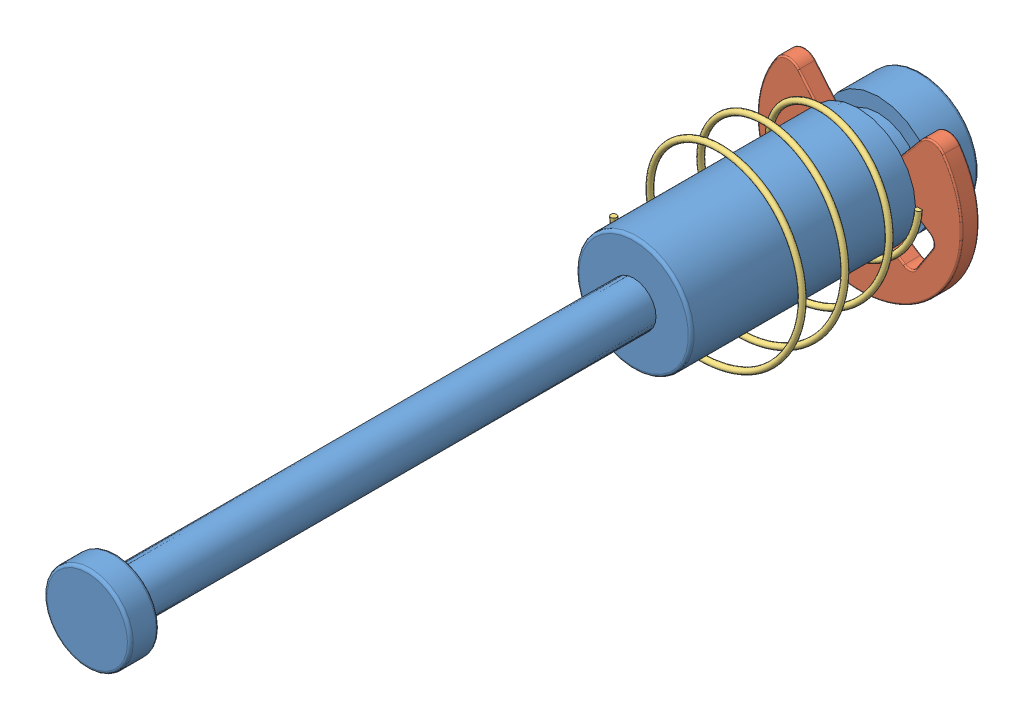
SolidWorks assembly Shaft Assem, configuration Default. Lengths in mm.
Overall size (7.1 6.76 29).
3 component instances, 3 part files, 5 mates.
Components (placement in the parent):
- Shaft-1: Shaft [Default] at origin size (4 4 29)
- Circlip-1: Circlip [Default] at (0 0 -8.45) size (7.1 5.79 0.6)
- Spring-1: Spring [Default] at (0 0 -2.3) x (-1 0 0) z (0 0 -1) size (6.3 6.5 5.85)
Mates (geometry in assembly coordinates):
- Coincident2: coordinate: point of Shaft-1; point of assembly
- Distance1: distance = 0.05 mm anti-aligned: plane of Shaft-1 through (0 2 -8.5) normal (0 0 1); plane of Circlip-1 through (0 0 -8.45) normal (0 0 -1)
- Coincident4: coincident anti-aligned: plane of Shaft-1 through (0 0 0) normal (1 0 0); plane of Spring-1 through (0 0 -2.3) normal (-1 0 0)
- Coincident5: coincident aligned: plane of Shaft-1 through (0 0 0) normal (0 1 0); plane of Spring-1
- Distance2: distance = 2.3 mm anti-aligned: plane of Spring-1 through (0 0 -2.3) normal (0 0 -1); plane of Shaft-1 through (0 0 0) normal (0 0 1)
